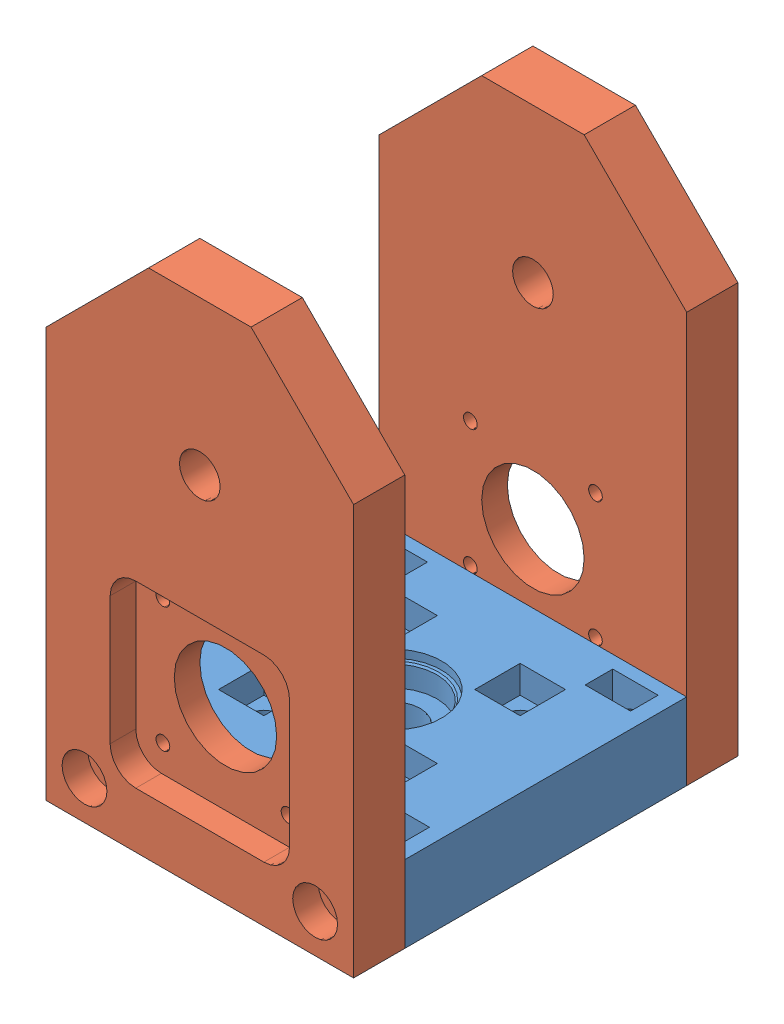
SolidWorks assembly base, configuration Default. Lengths in mm.
Overall size (76.2 127 95.25).
3 component instances, 2 part files, 4 mates.
Components (placement in the parent):
- base mount-1: base mount [Default] at origin size (76.2 19.05 69.85)
- base wall-1: base wall [Default] at (0 79.375 41.275) size (76.2 127 12.7)
- base wall-2: base wall [Default] at (0 79.375 -41.275) x (-1 0 0) z (0 0 -1) size (76.2 127 12.7)
Mates (geometry in assembly coordinates):
- Coincident1: coordinate: point of base mount-1
- Coincident2: coincident anti-aligned: plane of base mount-1 through (-38.1 9.525 34.925) normal (0 0 1); plane of base wall-1 through (0 79.375 34.925) normal (0 0 -1)
- Concentric1: concentric aligned: cylinder of base mount-1 through (-28.575 0 34.925) axis (0 0 1) radius 3.3782; cylinder of base wall-1 through (-28.575 0 47.625) axis (0 0 1) radius 3.3782
- Concentric2: concentric aligned: cylinder of base wall-1 through (28.575 0 47.625) axis (0 0 1) radius 3.3782; cylinder of base mount-1 through (28.575 0 34.925) axis (0 0 1) radius 3.3782
